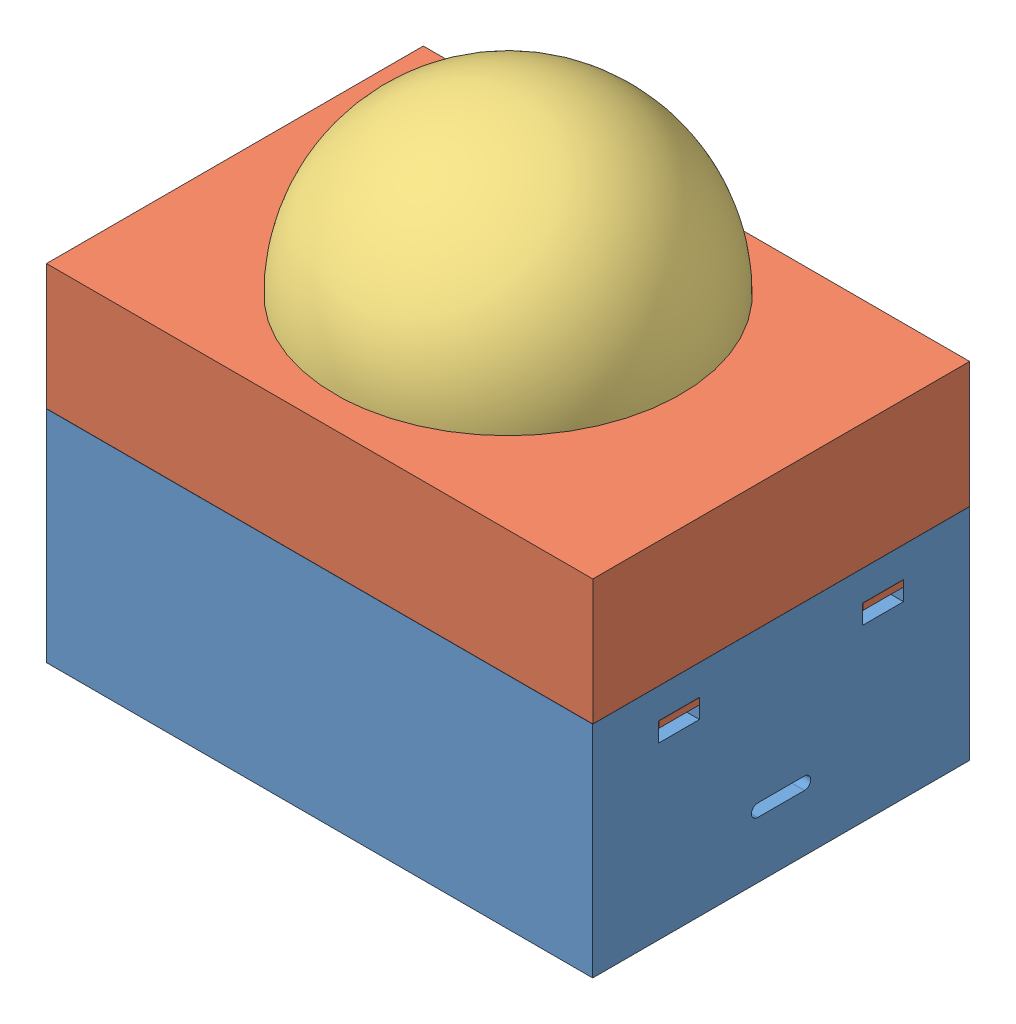
SolidWorks assembly Assem2, configuration Default. Lengths in mm.
Overall size (87.04 87.53 60.02).
7 component instances, 4 part files, 0 mates.
Components (placement in the parent):
- ButtonHousingUpdated-1: ButtonHousingUpdated [Default] at origin size (87 35 60)
- ButtonTopUpdated-2: ButtonTopUpdated [Default] at (23.6308 35.0644 -7.3133) size (87 27.85 60)
- ButtonTopUpdatedH-2: ButtonTopUpdatedH [Default] at (6.5749 57.5157 -6.4001) size (55 39.5 55)
- ButtonBase-1: ButtonBase [Default] at (45.5883 -0.017 19.3594) size (5 2.5 5)
- ButtonBase-2: ButtonBase [Default] at (-32.0708 -0.0002 -31.5425) size (5 2.5 5)
- ButtonBase-3: ButtonBase [Default] at (-31.7938 0.0408 18.2646) size (5 2.5 5)
- ButtonBase-4: ButtonBase [Default] at (45.3299 0.0009 -32.3947) size (5 2.5 5)
